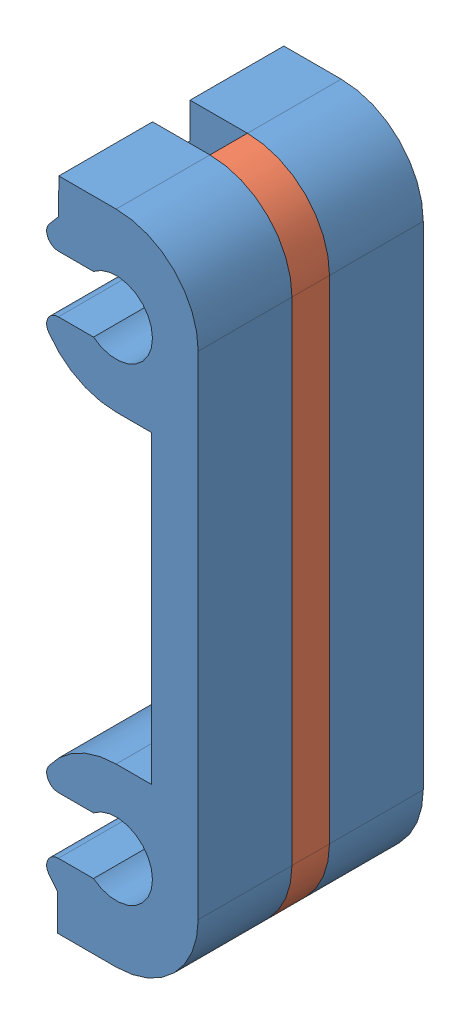
SolidWorks assembly enclosure-compatible module laser-cut 20x20, configuration Default. Lengths in mm.
Overall size (6.46 28 9.6).
12 component instances, 8 part files, 18 mates.
Components (placement in the parent):
- enclosure-compatible module 20x20-2: enclosure-compatible module 20x20 [Default] at (8.2244 14.4247 23.4545) size (26 26.5 1.62) (hidden)
- edge connector wall-1: edge connector wall [Default] at (8.2244 26.9247 23.4545) x (1 0 0) z (0 1 0) size (14.07 7.5 5.35) (hidden)
- enclosure end piece jacdac 20-1: enclosure end piece jacdac 20 [Default] at (-18.7861 26.9247 18.5047) x (1 0 0) z (0 1 0) size (19.11 11.6 1.5) (hidden)
- enclosure surround 3mm 20x20-1: enclosure surround 3mm 20x20 [Default] at (8.2244 14.4247 23.4545) x (-1 0 0) z (0 0 -1) size (6.46 28 4)
- enclosure lid 20x20-1: enclosure lid 20x20 [Default] at (8.2244 14.4247 19.4545) x (-1 0 0) z (0 0 -1) size (27 28 1) (hidden)
- enclosure surround 3mm 20x20-2: enclosure surround 3mm 20x20 [Default] at (8.2244 14.4247 29.0545) x (-1 0 0) z (0 0 -1) size (6.46 28 4)
- enclosure lid 20x20-2: enclosure lid 20x20 [Default] at (8.2244 14.4247 30.0545) x (-1 0 0) z (0 0 -1) size (27 28 1) (hidden)
- enclosure bumper 20x20-1: enclosure bumper 20x20 [Default] at (-1.7756 26.9247 23.5047) x (0 1 0) z (-1 0 0) size (30 15.7 29) (hidden)
- enclosure surround 3mm 20x20-3: enclosure surround 3mm 20x20 [Default] at (8.2244 14.4247 19.4545) size (6.46 28 4) (hidden)
- enclosure end piece solid 20-1: enclosure end piece solid 20 [Default] at (5.2591 1.9247 27.0045) x (1 0 0) z (0 -1 0) size (19.11 11.6 1.5) (hidden)
- enclosure surround 3mm 20x20-4: enclosure surround 3mm 20x20 [Default] at (8.2244 14.4247 25.0545) size (6.46 28 4) (hidden)
- enclosure surround joining piece-1: enclosure surround joining piece [Default] at (8.2244 14.4247 23.4545) size (3.5 28 1.6)
Mates (geometry in assembly coordinates):
- InPlace1: in place: plane of ? through (-5.2756 27.9247 25.0545) normal (0 1 0); plane of ? through (0 27.9247 0) normal (0 1 0); moOrthogonalPlaneRef_w of ? through (-5.2756 27.9247 25.0545) normal (0 1 0); plane of ? through (0 27.9247 0) normal (0 0 -1); plane of ? through (-5.2756 27.9247 25.0545) normal (0 1 0); plane of ? through (0 27.9247 0) normal (1 0 0); plane of ? through (-4.2756 26.9247 25.0545) normal (0 1 0); unknown of edge connector wall-1
- Coincident1: coincident: plane of enclosure-compatible module 20x20-2; plane of edge connector wall-1
- Coincident2: coincident: moOrthogonalPlaneRef_w of enclosure-compatible module 20x20-2 through (8.2244 26.9247 23.4545) normal (0 0 -1); plane of edge connector wall-1 through (8.2244 26.9247 23.4545) normal (0 0 -1)
- Coincident3: coincident: moOrthogonalPlaneRef_w of enclosure-compatible module 20x20-2 through (8.2244 26.9247 23.4545) normal (-1 0 0); plane of edge connector wall-1 through (8.2244 26.9247 23.4545) normal (1 0 0)
- InPlace3: in place: plane of ? through (8.2244 14.4247 23.4545) normal (0 0 -1); plane of ? through (0 0 23.4545) normal (0 0 -1); plane of ? through (8.2244 14.4247 23.4545) normal (0 0 -1); plane of ? through (0 0 23.4545) normal (0 1 0); plane of ? through (8.2244 14.4247 23.4545) normal (0 0 -1); plane of ? through (0 0 23.4545) normal (-1 0 0); plane of ? through (8.2244 14.4247 23.4545) normal (0 0 -1); unknown of enclosure surround 3mm 20x20-1
- Coincident7: coincident: plane of enclosure-compatible module 20x20-2; plane of enclosure surround 3mm 20x20-1
- Coincident8: coincident: moOrthogonalPlaneRef_w of enclosure-compatible module 20x20-2 through (8.2244 14.4247 23.4545) normal (0 1 0); plane of enclosure surround 3mm 20x20-1 through (8.2244 14.4247 23.4545) normal (0 1 0)
- Coincident9: coincident: moOrthogonalPlaneRef_w of enclosure-compatible module 20x20-2 through (8.2244 14.4247 23.4545) normal (1 0 0); plane of enclosure surround 3mm 20x20-1 through (8.2244 14.4247 23.4545) normal (-1 0 0)
- InPlace4: in place: plane of enclosure surround 3mm 20x20-1 through (-1.7756 26.4247 20.4545) normal (0 0 -1); plane of ? through (0 0 20.4545) normal (0 0 -1); plane of enclosure surround 3mm 20x20-1 through (-1.7756 26.4247 20.4545) normal (0 0 -1); plane of ? through (0 0 20.4545) normal (0 1 0); plane of enclosure surround 3mm 20x20-1 through (-1.7756 26.4247 20.4545) normal (0 0 -1); plane of ? through (0 0 20.4545) normal (-1 0 0); plane of enclosure surround 3mm 20x20-1 through (18.2244 24.4247 19.4545) normal (0 0 -1); unknown of enclosure lid 20x20-1
- Coincident10: coincident: plane of enclosure surround 3mm 20x20-1; plane of enclosure lid 20x20-1
- Coincident11: coincident: moOrthogonalPlaneRef_w of enclosure surround 3mm 20x20-1 through (8.2244 14.4247 19.4545) normal (0 1 0); plane of enclosure lid 20x20-1 through (8.2244 14.4247 19.4545) normal (0 1 0)
- Coincident12: coincident: moOrthogonalPlaneRef_w of enclosure surround 3mm 20x20-1 through (8.2244 14.4247 19.4545) normal (1 0 0); plane of enclosure lid 20x20-1 through (8.2244 14.4247 19.4545) normal (-1 0 0)
- Coincident20: coincident: plane of enclosure-compatible module 20x20-2 through (-4.2756 26.9247 25.0545) normal (0 1 0); plane of enclosure end piece jacdac 20-1 through (-18.7861 26.9247 18.5047) normal (0 -1 0)
- Coincident22: coincident: plane of enclosure-compatible module 20x20-2 through (-4.2756 1.9247 25.0545) normal (0 -1 0); plane of enclosure end piece solid 20-1 through (15.4781 1.9247 29.7545) normal (0 1 0)
- InPlace5: in place: plane of enclosure surround 3mm 20x20-1 through (18.2244 24.4247 23.4545) normal (0 0 1); plane of ? through (0 0 23.4545) normal (0 0 1); plane of enclosure surround 3mm 20x20-1 through (18.2244 24.4247 23.4545) normal (0 0 1); plane of ? through (0 0 23.4545) normal (0 1 0); plane of enclosure surround 3mm 20x20-1 through (18.2244 24.4247 23.4545) normal (0 0 1); plane of ? through (0 0 23.4545) normal (1 0 0); plane of enclosure surround 3mm 20x20-1 through (18.2244 24.4247 23.4545) normal (0 0 1); unknown of ?
- Coincident23: coincident: plane of enclosure surround 3mm 20x20-1; plane of enclosure surround joining piece-1
- Coincident24: coincident: moOrthogonalPlaneRef_w of enclosure surround 3mm 20x20-1 through (8.2244 14.4247 23.4545) normal (0 1 0); plane of enclosure surround joining piece-1 through (8.2244 14.4247 23.4545) normal (0 1 0)
- Coincident25: coincident: moOrthogonalPlaneRef_w of enclosure surround 3mm 20x20-1 through (8.2244 14.4247 23.4545) normal (-1 0 0); plane of enclosure surround joining piece-1 through (8.2244 14.4247 23.4545) normal (1 0 0)
